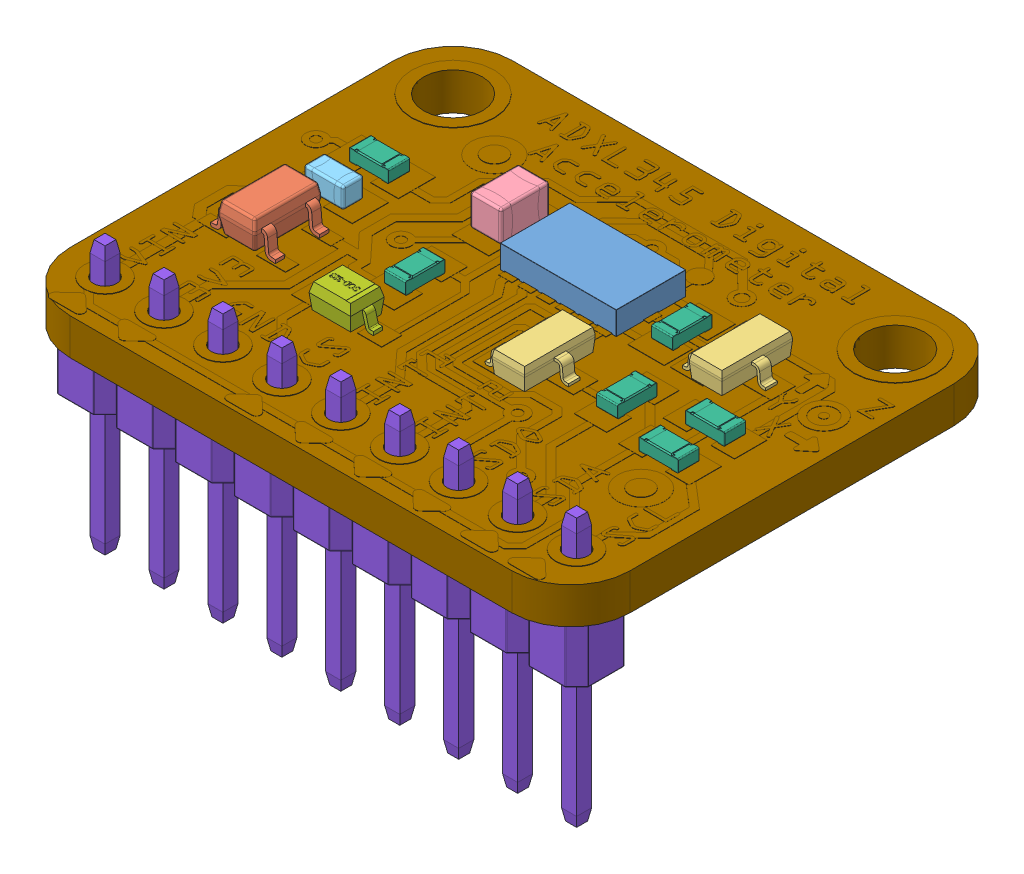
SolidWorks assembly ADXL345 Digital Accelerometer, configuration Default. Lengths in mm.
Overall size (24.13 11.59 19.05).
24 component instances, 9 part files, 0 mates.
Components (placement in the parent):
- ADXL345 Digital Accelerometer.step-1: ADXL345 Digital Accelerometer.step [Default] at origin size (24.13 11.59 19.05)
  - 3x5 LGA Package.step-1: 3x5 LGA Package.step [Default] at (13.2372 0.005 -11.7916) x (0 0 1) z (-1 0 0) size (3 1 5)
  - SOT-23-5.step-1: SOT-23-5.step [Default] at (1.7859 0.015 -5.313) size (2.8 1.45 2.9)
  - SOT 23-3.step-1: SOT 23-3.step [Default] at (12.7718 0.115 -6.1282) x (0 0 1) z (-1 0 0) size (3.04 1.04 2.64)
  - SOT 23-3.step-2: SOT 23-3.step [Default] at (17.1718 0.115 -10.2282) x (0 0 1) z (-1 0 0) size (3.04 1.04 2.64)
  - Capacitor 0805 T1.35 BN.step-1: Capacitor 0805 T1.35 BN.step [Default] at (6.0126 0.685 -10.7496) x (0 0 -1) z (1 0 0) size (2.1 1.35 1.35)
  - Capacitor 0603 T0.9 BN.step-1: Capacitor 0603 T0.9 BN.step [Default] at (1.8267 0.465 -8.4833) size (1.7 0.9 0.9)
  - Resistor 0603.step-1: Resistor 0603.step [Default] at (0.9479 -0.035 -10.4764) size (1.7 0.55 0.9)
  - Resistor 0603.step-2: Resistor 0603.step [Default] at (17.9907 -0.035 -5.913) size (1.7 0.55 0.9)
  - Resistor 0603.step-3: Resistor 0603.step [Default] at (17.9907 -0.035 -7.913) size (1.7 0.55 0.9)
  - Resistor 0603.step-4: Resistor 0603.step [Default] at (15.4553 -0.035 -5.7278) x (0 0 -1) z (1 0 0) size (1.7 0.55 0.9)
  - Resistor 0603.step-5: Resistor 0603.step [Default] at (14.0899 -0.035 -9.4639) x (0 0 -1) z (1 0 0) size (1.7 0.55 0.9)
  - Resistor 0603.step-6: Resistor 0603.step [Default] at (6.2819 -0.035 -5.7657) x (0 0 -1) z (1 0 0) size (1.7 0.55 0.9)
  - SOD-323 Package.step-1: SOD-323 Package.step [Default] at (6.619 -0.005 -3.7923) x (0 0 -1) z (1 0 0) size (1.45 1.15 2.7)
  - Male Pin Header.step-1: Male Pin Header.step [Default] at (-1.27 -4.13 -1.2719) size (2.54 11.54 2.54)
  - Male Pin Header.step-2: Male Pin Header.step [Default] at (1.27 -4.13 -1.2719) size (2.54 11.54 2.54)
  - Male Pin Header.step-3: Male Pin Header.step [Default] at (3.81 -4.13 -1.2719) size (2.54 11.54 2.54)
  - Male Pin Header.step-4: Male Pin Header.step [Default] at (6.35 -4.13 -1.2719) size (2.54 11.54 2.54)
  - Male Pin Header.step-5: Male Pin Header.step [Default] at (8.89 -4.13 -1.2719) size (2.54 11.54 2.54)
  - Male Pin Header.step-6: Male Pin Header.step [Default] at (11.43 -4.13 -1.2719) size (2.54 11.54 2.54)
  - Male Pin Header.step-7: Male Pin Header.step [Default] at (13.97 -4.13 -1.2719) size (2.54 11.54 2.54)
  - Male Pin Header.step-8: Male Pin Header.step [Default] at (16.51 -4.13 -1.2719) size (2.54 11.54 2.54)
  - Male Pin Header.step-9: Male Pin Header.step [Default] at (19.05 -4.13 -1.2719) size (2.54 11.54 2.54)
  - ADXL345 Digital Accelerometer.step-1: ADXL345 Digital Accelerometer.step [Default] at origin size (24.13 1.61 19.05)
